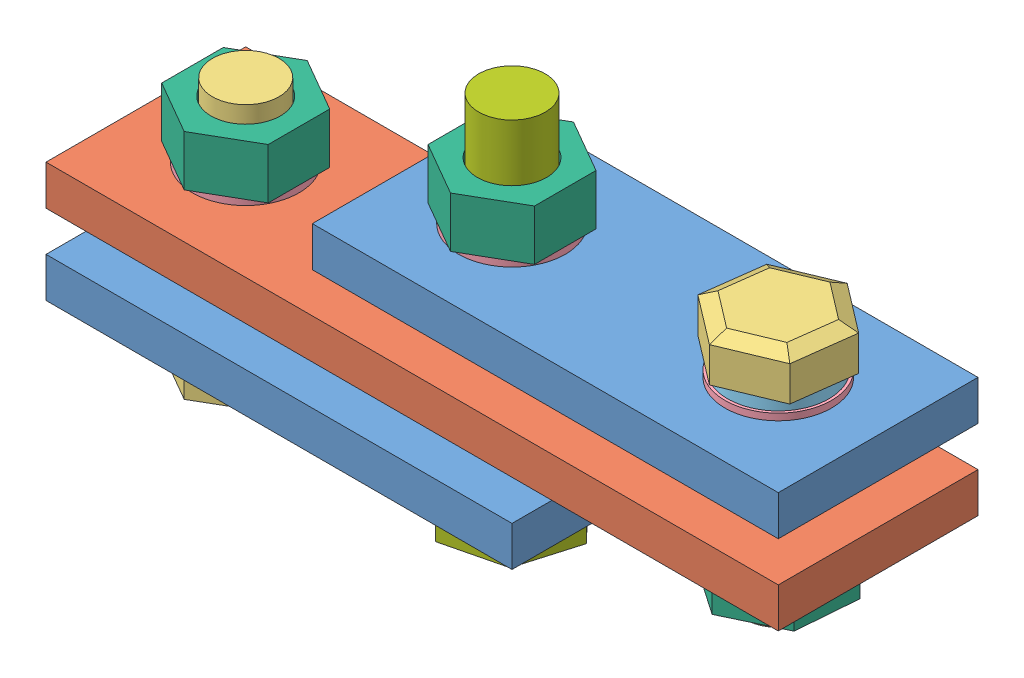
SolidWorks assembly СбКоробка, configuration По умолчанию. Lengths in mm.
Overall size (55 28.2 15).
18 component instances, 7 part files, 36 mates.
Components (placement in the parent):
- Планка2-1: Планка2 [По умолчанию] at (10 6 0) size (35 3 15)
- Планка-1: Планка [По умолчанию] at origin size (55 3 15)
- Планка2-2: Планка2 [По умолчанию] at (-10 -6 0) size (35 3 15)
- БолтМ5_16-1: БолтМ5_16 [По умолчанию] at (-20 -10.7 0) size (8 19.2 9.24)
- ШайбаМ5-1: ШайбаМ5 [По умолчанию] at (0 -6.5 0) size (8 0.5 8)
- ГроверМ5-1: ГроверМ5 [По умолчанию] at (0 -7.5 0) size (7.6 1 7.6)
- ГайкаМ5-1: ГайкаМ5 [По умолчанию] at (0 9.5 0) size (8 3.8 9.24)
- ШайбаМ5-2: ШайбаМ5 [По умолчанию] at (0 9 0) size (8 0.5 8)
- БолтМ5_25-1: БолтМ5_25 [По умолчанию] at (0 -10.7 0) x (0.959724 0 0.280943) z (-0.280943 0 0.959724) size (8 28.2 9.24)
- БолтМ5_16-2: БолтМ5_16 [По умолчанию] at (20 13.7 0) x (-0.991705 0 -0.128532) z (-0.128532 0 0.991705) size (8 19.2 9.24)
- ШайбаМ5-3: ШайбаМ5 [По умолчанию] at (-20 -6.5 0) size (8 0.5 8)
- ГроверМ5-2: ГроверМ5 [По умолчанию] at (-20 -7.5 0) size (7.6 1 7.6)
- ШайбаМ5-4: ШайбаМ5 [По умолчанию] at (-20 3 0) size (8 0.5 8)
- ГайкаМ5-2: ГайкаМ5 [По умолчанию] at (-20 3.5 0) size (8 3.8 9.24)
- ГайкаМ5-3: ГайкаМ5 [По умолчанию] at (20 -4.3 0) x (0.99685 0 0.079314) z (-0.079314 0 0.99685) size (8 3.8 9.24)
- ШайбаМ5-5: ШайбаМ5 [По умолчанию] at (20 9 0) size (8 0.5 8)
- ГроверМ5-3: ГроверМ5 [По умолчанию] at (20 9.5 0) size (7.6 1 7.6)
- ШайбаМ5-6: ШайбаМ5 [По умолчанию] at (20 -0.5 0) size (8 0.5 8)
Mates (geometry in assembly coordinates):
- Совпадение1: coordinate: point of Планка-1
- Концентричный1: concentric aligned: cylinder of Планка2-1 through (0 9 0) axis (0 -1 0) radius 2.6; cylinder of Планка-1 through (0 3 0) axis (0 -1 0) radius 2.6
- Расстояние1: distance = 3 mm anti-aligned: plane of Планка2-1 through (10 6 0) normal (0 -1 0); plane of Планка-1 through (0 3 0) normal (0 1 0)
- Концентричный2: concentric aligned: cylinder of Планка-1 through (0 3 0) axis (0 -1 0) radius 2.6; cylinder of Планка2-2 through (0 -3 0) axis (0 -1 0) radius 2.6
- Расстояние2: distance = 3 mm anti-aligned: plane of Планка-1 through (0 0 0) normal (0 -1 0); plane of Планка2-2 through (-10 -3 0) normal (0 1 0)
- Совпадение4: coincident aligned: plane of Планка-1 through (-27.5 3 7.5) normal (0 0 1); plane of Планка2-2 through (-27.5 -3 7.5) normal (0 0 1)
- Совпадение5: coincident aligned: plane of Планка2-1 through (-7.5 9 7.5) normal (0 0 1); plane of Планка-1 through (-27.5 3 7.5) normal (0 0 1)
- Совпадение6: coincident anti-aligned: plane of Планка2-2 through (-10 -6 0) normal (0 -1 0); plane of ШайбаМ5-1 through (0 -6 0) normal (0 1 0)
- Совпадение7: coincident anti-aligned: plane of ШайбаМ5-1 through (0 -6.5 0) normal (0 -1 0); plane of ГроверМ5-1 through (0 -6.5 0) normal (0 1 0)
- Совпадение9: coincident anti-aligned: plane of Планка2-1 through (10 9 0) normal (0 1 0); plane of ШайбаМ5-2 through (0 9 0) normal (0 -1 0)
- Совпадение10: coincident anti-aligned: plane of ГайкаМ5-1 through (0 9.5 0) normal (0 -1 0); plane of ШайбаМ5-2 through (0 9.5 0) normal (0 1 0)
- Концентричный8: concentric aligned: cylinder of Планка-1 through (-20 3 0) axis (0 -1 0) radius 2.6; cylinder of БолтМ5_16-1 through (-20 8.5 0) axis (0 -1 0) radius 2.5
- Концентричный9: concentric aligned: cylinder of Планка2-2 through (0 -3 0) axis (0 -1 0) radius 2.6; cylinder of БолтМ5_25-1 through (0 17.5 0) axis (0 -1 0) radius 2.5
- Концентричный10: concentric aligned: cylinder of ГроверМ5-1 through (0 -6.5 0) axis (0 -1 0) radius 2.6; cylinder of БолтМ5_25-1 through (0 17.5 0) axis (0 -1 0) radius 2.5
- Совпадение11: coincident anti-aligned: plane of ГроверМ5-1 through (0 -7.5 0) normal (0 -1 0); plane of БолтМ5_25-1 through (0 -7.5 0) normal (0 1 0)
- Концентричный11: concentric aligned: cylinder of ШайбаМ5-2 through (0 9.5 0) axis (0 -1 0) radius 2.6; cylinder of БолтМ5_25-1 through (0 17.5 0) axis (0 -1 0) radius 2.5
- Концентричный12: concentric aligned: cylinder of ГайкаМ5-1 through (0 13.3 0) axis (0 -1 0) radius 2.6; cylinder of БолтМ5_25-1 through (0 17.5 0) axis (0 -1 0) radius 2.5
- Концентричный13: concentric aligned: cylinder of БолтМ5_16-1 through (-20 8.5 0) axis (0 -1 0) radius 2.5; cylinder of ШайбаМ5-3 through (-20 -6 0) axis (0 -1 0) radius 2.6
- Совпадение12: coincident anti-aligned: plane of Планка2-2 through (-10 -6 0) normal (0 -1 0); plane of ШайбаМ5-3 through (-20 -6 0) normal (0 1 0)
- Совпадение13: coincident anti-aligned: plane of ШайбаМ5-3 through (-20 -6.5 0) normal (0 -1 0); plane of ГроверМ5-2 through (-20 -6.5 0) normal (0 1 0)
- Концентричный14: concentric aligned: cylinder of БолтМ5_16-1 through (-20 8.5 0) axis (0 -1 0) radius 2.5; cylinder of ГроверМ5-2 through (-20 -6.5 0) axis (0 -1 0) radius 2.6
- Совпадение14: coincident anti-aligned: plane of БолтМ5_16-1 through (-20 -7.5 0) normal (0 1 0); plane of ГроверМ5-2 through (-20 -7.5 0) normal (0 -1 0)
- Концентричный15: concentric aligned: cylinder of БолтМ5_16-1 through (-20 8.5 0) axis (0 -1 0) radius 2.5; cylinder of ШайбаМ5-4 through (-20 3.5 0) axis (0 -1 0) radius 2.6
- Совпадение15: coincident anti-aligned: plane of Планка-1 through (0 3 0) normal (0 1 0); plane of ШайбаМ5-4 through (-20 3 0) normal (0 -1 0)
- Концентричный16: concentric aligned: cylinder of БолтМ5_16-1 through (-20 8.5 0) axis (0 -1 0) radius 2.5; cylinder of ГайкаМ5-2 through (-20 7.3 0) axis (0 -1 0) radius 2.6
- Совпадение16: coincident anti-aligned: plane of ШайбаМ5-4 through (-20 3.5 0) normal (0 1 0); plane of ГайкаМ5-2 through (-20 3.5 0) normal (0 -1 0)
- Совпадение17: coincident anti-aligned: plane of Планка2-1 through (10 9 0) normal (0 1 0); plane of ШайбаМ5-5 through (20 9 0) normal (0 -1 0)
- Концентричный17: concentric aligned: cylinder of Планка2-1 through (20 9 0) axis (0 -1 0) radius 2.6; cylinder of ШайбаМ5-5 through (20 9.5 0) axis (0 -1 0) radius 2.6
- Совпадение18: coincident anti-aligned: circle of ШайбаМ5-5; cylinder of ГроверМ5-3 through (20 10.5 0) axis (0 -1 0) radius 2.6
- Совпадение19: coincident anti-aligned: plane of ШайбаМ5-5 through (20 9.5 0) normal (0 1 0); plane of ГроверМ5-3 through (20 9.5 0) normal (0 -1 0)
- Концентричный18: concentric anti-aligned: cylinder of Планка2-1 through (20 9 0) axis (0 -1 0) radius 2.6; cylinder of БолтМ5_16-2 through (20 -5.5 0) axis (0 1 0) radius 2.5
- Совпадение22: coincident anti-aligned: plane of БолтМ5_16-2 through (20 10.5 0) normal (0 -1 0); plane of ГроверМ5-3 through (20 10.5 0) normal (0 1 0)
- Концентричный19: concentric anti-aligned: cylinder of БолтМ5_16-2 through (20 -5.5 0) axis (0 1 0) radius 2.5; cylinder of ШайбаМ5-6 through (20 0 0) axis (0 -1 0) radius 2.6
- Совпадение23: coincident anti-aligned: plane of Планка-1 through (0 0 0) normal (0 -1 0); plane of ШайбаМ5-6 through (20 0 0) normal (0 1 0)
- Концентричный20: concentric anti-aligned: cylinder of БолтМ5_16-2 through (20 -5.5 0) axis (0 1 0) radius 2.5; cylinder of ГайкаМ5-3 through (20 -0.5 0) axis (0 -1 0) radius 2.6
- Совпадение24: coincident anti-aligned: plane of ГайкаМ5-3 through (20 -0.5 0) normal (0 1 0); plane of ШайбаМ5-6 through (20 -0.5 0) normal (0 -1 0)
